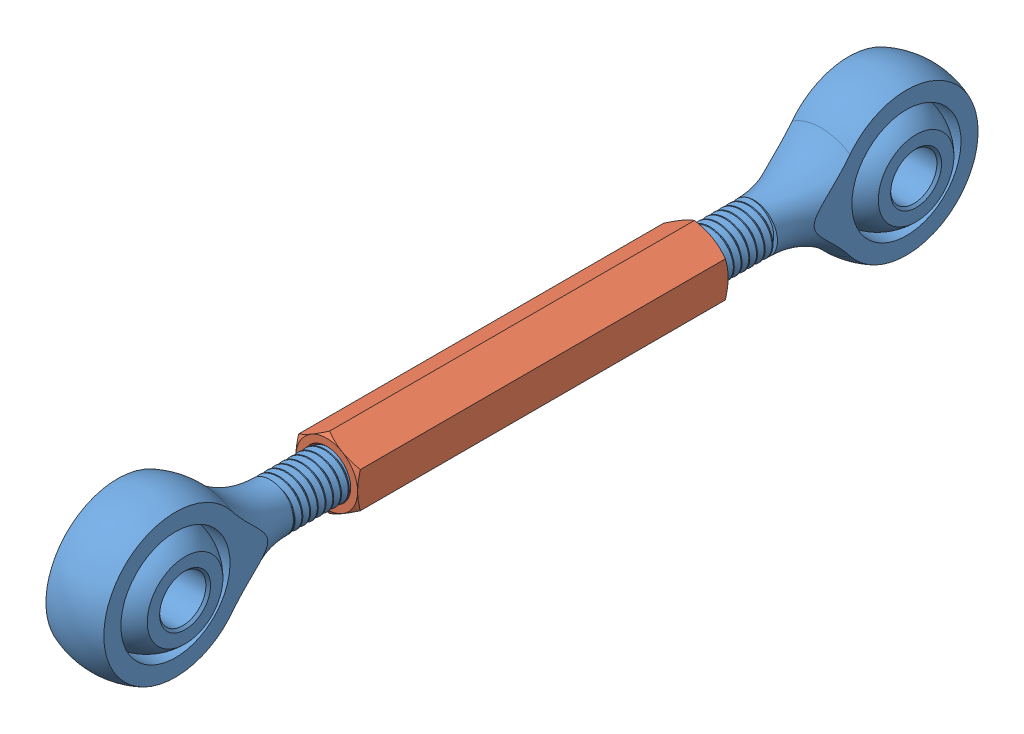
SolidWorks assembly Outboard Autothrottle Linkage Rod, configuration Default. Lengths in mm.
Overall size (7.94 15.88 91.05).
3 component instances, 2 part files, 6 mates.
Components (placement in the parent):
- 60645K111_STEEL BALL JOINT ROD END RH-1: 60645K111_STEEL BALL JOINT ROD END RH [60645K111] at (-38.8866 -18.9453 -71.8464) x (0 1 -0.000005) z (-1 0 0) size (15.88 39.82 7.94)
- 60645K111_STEEL BALL JOINT ROD END RH-2: 60645K111_STEEL BALL JOINT ROD END RH [60645K111] at (-38.8866 -18.9451 -22.0711) x (0 1 -0.000005) z (1 0 0) size (15.88 39.82 7.94)
- 91780A190 - STANDOFF, HEX, FEMALE, 10-32 X 1.50 L X .25 HEX, ALUMINUM-1: 91780A190 - STANDOFF, HEX, FEMALE, 10-32 X 1.50 L X .25 HEX, ALUMINUM [91780A190] at (-38.8866 -18.9452 -46.9588) x (1 0 0) z (0 0.000005 1) size (6.35 7.33 38.72)
Mates (geometry in assembly coordinates):
- Distance33: distance = 11.6753 mm anti-aligned: plane of 60645K111_STEEL BALL JOINT ROD END RH-1 through (-38.8866 -18.9452 -52.7964) normal (0 0.000005 1); plane of 60645K111_STEEL BALL JOINT ROD END RH-2 through (-38.8866 -18.9451 -41.1211) normal (0 -0.000005 -1)
- Coincident1: coincident aligned: plane of 60645K111_STEEL BALL JOINT ROD END RH-1 through (-38.8866 -18.9453 -71.8464) normal (0 1 -0.000005); plane of 60645K111_STEEL BALL JOINT ROD END RH-2 through (-38.8866 -18.9451 -22.0711) normal (0 1 -0.000005)
- Concentric265: concentric anti-aligned: circle of 60645K111_STEEL BALL JOINT ROD END RH-1; circle of 60645K111_STEEL BALL JOINT ROD END RH-2
- Coincident2: coincident: plane of 60645K111_STEEL BALL JOINT ROD END RH-1 through (-38.8866 -18.9453 -71.8464) normal (-1 0 0); plane of 91780A190 - STANDOFF, HEX, FEMALE, 10-32 X 1.50 L X .25 HEX, ALUMINUM-1 through (-38.8866 -18.9452 -46.9588) normal (1 0 0)
- Width14: width: plane of 91780A190 - STANDOFF, HEX, FEMALE, 10-32 X 1.50 L X .25 HEX, ALUMINUM-1 through (-38.8866 -15.2791 -66.0088) normal (0 -0.000005 -1); plane of 60645K111_STEEL BALL JOINT ROD END RH-2 through (-38.8866 -15.2789 -27.9088) normal (0 0.000005 1); plane of 91780A190 - STANDOFF, HEX, FEMALE, 10-32 X 1.50 L X .25 HEX, ALUMINUM-1 through (-38.8866 -18.9451 -41.1211) normal (0 -0.000005 -1); plane of 60645K111_STEEL BALL JOINT ROD END RH-1 through (-38.8866 -18.9452 -52.7964) normal (0 0.000005 1)
- Concentric266: concentric aligned: circle of 60645K111_STEEL BALL JOINT ROD END RH-2; circle of 91780A190 - STANDOFF, HEX, FEMALE, 10-32 X 1.50 L X .25 HEX, ALUMINUM-1
